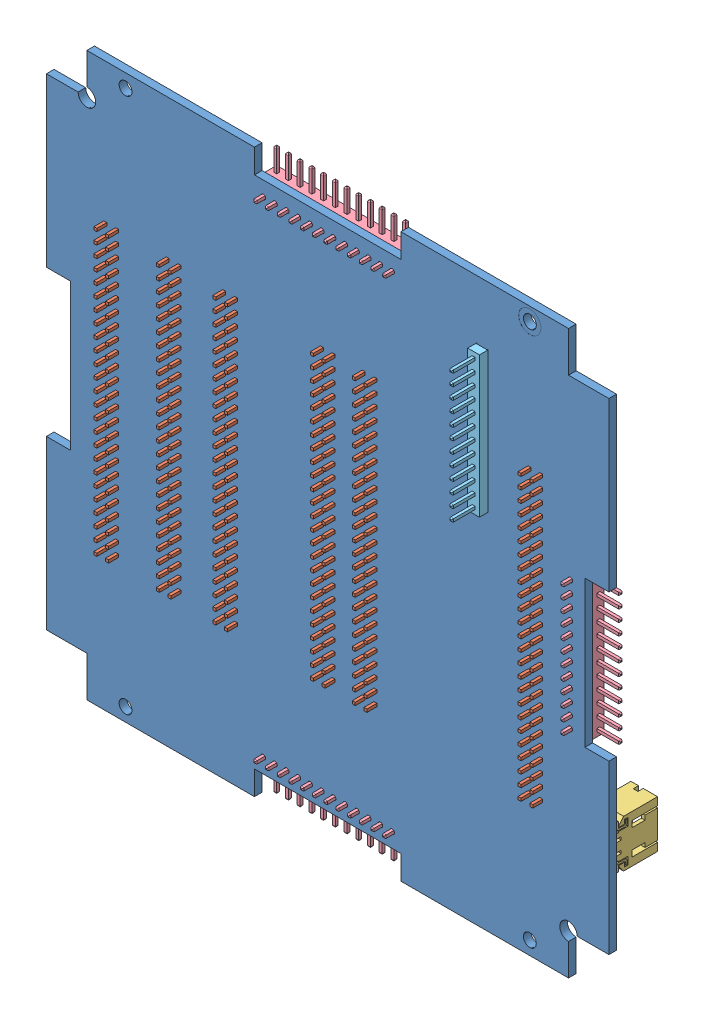
SolidWorks assembly B3_back_board, configuration ﾃﾞﾌｫﾙﾄ. Lengths in mm.
Overall size (96 96 13.7).
13 component instances, 5 part files, 36 mates.
Components (placement in the parent):
- B3_bottom_panel-1: B3_bottom_panel [ﾃﾞﾌｫﾙﾄ] at (2.0992 1.8569 97) size (96 96 1.3)
- B3_50pin-4: B3_50pin [ﾃﾞﾌｫﾙﾄ] at (-24.2008 1.8569 97) x (0 -1 0) z (0 0 -1) size (50 4 7.2)
- B3_50pin-6: B3_50pin [ﾃﾞﾌｫﾙﾄ] at (2.0992 1.8569 97) x (0 -1 0) z (0 0 -1) size (50 4 7.2)
- B3_50pin-8: B3_50pin [ﾃﾞﾌｫﾙﾄ] at (-34.8508 1.8569 97) x (0 -1 0) z (0 0 -1) size (50 4 7.2)
- MOLEX_554600272-1: MOLEX_554600272 [Default] at (-43.6258 27.8069 93.5) x (0 1 0) z (0 0 -1) size (8.1 6.55 7)
- MOLEX_554600272-2: MOLEX_554600272 [Default] at (47.8242 -24.0931 93.5) x (0 -1 0) z (0 0 -1) size (8.1 6.55 7)
- B3_50pin-9: B3_50pin [ﾃﾞﾌｫﾙﾄ] at (37.5492 1.8569 97) x (0 -1 0) z (0 0 -1) size (50 4 7.2)
- B3_50pin-11: B3_50pin [ﾃﾞﾌｫﾙﾄ] at (-14.5508 1.8569 97) x (0 -1 0) z (0 0 -1) size (50 4 7.2)
- Solar_panel_ML-1: Solar_panel_ML [Default] at (-9.9008 45.7569 95) x (0 0 1) z (-1 0 0) size (4.85 6.65 24)
- Solar_panel_ML-2: Solar_panel_ML [Default] at (45.9992 13.8569 95) x (0 0 1) z (0 1 0) size (4.85 6.65 24)
- Solar_panel_ML-3: Solar_panel_ML [Default] at (14.0992 -42.0431 95) x (0 0 1) z (1 0 0) size (4.85 6.65 24)
- Solar panel_M-2: Solar panel_M [Default] at (27.4992 15.8569 99.8) x (1 0 0) z (0 -1 0) size (2 8.15 24)
- B3_50pin-12: B3_50pin [ﾃﾞﾌｫﾙﾄ] at (9.2492 1.8569 97) x (0 1 0) z (0 0 -1) size (50 4 7.2)
Mates (geometry in assembly coordinates):
- Coincident11: coincident anti-aligned: plane of B3_bottom_panel-1 through (2.0992 1.8569 97) normal (0 0 -1); plane of B3_50pin-6 through (2.0992 1.8569 97) normal (0 0 1)
- Coincident14: coincident anti-aligned: plane of B3_bottom_panel-1 through (2.0992 1.8569 97) normal (0 0 -1); plane of B3_50pin-4 through (-24.2008 1.8569 97) normal (0 0 1)
- Coincident35: coincident anti-aligned: plane of B3_bottom_panel-1 through (2.0992 1.8569 97) normal (0 0 -1); plane of B3_50pin-8 through (-34.8508 1.8569 97) normal (0 0 1)
- Coincident36: coincident aligned: plane of B3_50pin-4 through (-26.2008 26.8569 92.8) normal (0 1 0); plane of B3_50pin-8 through (-36.8508 26.8569 92.8) normal (0 1 0)
- Coincident47: coincident aligned: plane of B3_50pin-6 through (0.0992 26.8569 92.8) normal (0 1 0); plane of B3_50pin-8 through (-36.8508 26.8569 92.8) normal (0 1 0)
- Coincident95: coincident anti-aligned: plane of B3_bottom_panel-1 through (2.0992 1.8569 97) normal (0 0 -1); plane of MOLEX_554600272-1 through (-43.6258 27.8069 97) normal (0 0 1)
- Distance46: distance = 11.1 mm aligned: plane of MOLEX_554600272-1 through (-45.9008 31.8569 97) normal (0 1 0); plane of B3_bottom_panel-1 through (-39.0008 42.9569 89.8) normal (0 1 0)
- Coincident101: coincident anti-aligned: plane of B3_bottom_panel-1 through (2.0992 1.8569 97) normal (0 0 -1); plane of MOLEX_554600272-2 through (47.8242 -24.0931 97) normal (0 0 1)
- Distance47: distance = 11.1 mm aligned: plane of MOLEX_554600272-2 through (50.0992 -28.1431 97) normal (0 -1 0); plane of B3_bottom_panel-1 through (50.1992 -39.2431 89.8) normal (0 -1 0)
- Coincident106: coincident anti-aligned: plane of B3_bottom_panel-1 through (2.0992 1.8569 97) normal (0 0 -1); plane of B3_50pin-11 through (-14.5508 1.8569 97) normal (0 0 1)
- Coincident108: coincident anti-aligned: plane of B3_bottom_panel-1 through (2.0992 1.8569 97) normal (0 0 -1); plane of B3_50pin-9 through (37.5492 1.8569 97) normal (0 0 1)
- Coincident109: coincident aligned: plane of B3_50pin-8 through (-36.8508 26.8569 92.8) normal (0 1 0); plane of B3_50pin-11 through (-16.5508 26.8569 92.8) normal (0 1 0)
- Coincident111: coincident aligned: plane of B3_50pin-8 through (-36.8508 26.8569 92.8) normal (0 1 0); plane of B3_50pin-9 through (35.5492 26.8569 92.8) normal (0 1 0)
- Distance49: distance = 4.95 mm aligned: plane of B3_50pin-8 through (-36.8508 26.8569 92.8) normal (-1 0 0); plane of B3_bottom_panel-1 through (-41.8008 14.3569 98.3) normal (-1 0 0)
- Distance50: distance = 15.6 mm aligned: plane of B3_50pin-4 through (-26.2008 26.8569 92.8) normal (-1 0 0); plane of B3_bottom_panel-1 through (-41.8008 14.3569 98.3) normal (-1 0 0)
- Distance51: distance = 25.25 mm aligned: plane of B3_50pin-11 through (-16.5508 26.8569 92.8) normal (-1 0 0); plane of B3_bottom_panel-1 through (-41.8008 14.3569 98.3) normal (-1 0 0)
- Distance53: distance = 41.9 mm aligned: plane of B3_50pin-6 through (0.0992 26.8569 92.8) normal (-1 0 0); plane of B3_bottom_panel-1 through (-41.8008 14.3569 98.3) normal (-1 0 0)
- Distance55: distance = 77.35 mm aligned: plane of B3_50pin-9 through (35.5492 26.8569 92.8) normal (-1 0 0); plane of B3_bottom_panel-1 through (-41.8008 14.3569 98.3) normal (-1 0 0)
- Coincident139: coincident aligned: plane of B3_bottom_panel-1 through (-45.9008 42.9569 98.3) normal (-1 0 0); plane of MOLEX_554600272-1 through (-45.9008 23.7569 97) normal (-1 0 0)
- Coincident140: coincident aligned: plane of B3_bottom_panel-1 through (50.0992 -39.2431 98.3) normal (1 0 0); plane of MOLEX_554600272-2 through (50.0992 -20.0431 97) normal (1 0 0)
- Distance63: distance = 23 mm aligned: plane of B3_50pin-8 through (-36.8508 26.8569 92.8) normal (0 1 0); plane of B3_bottom_panel-1 through (43.1992 49.8569 98.3) normal (0 1 0)
- Coincident142: coincident anti-aligned: plane of B3_bottom_panel-1 through (2.0992 1.8569 97) normal (0 0 -1); plane of Solar_panel_ML-1 through (14.0992 45.7569 97) normal (0 0 1)
- Coincident143: coincident aligned: plane of B3_bottom_panel-1 through (-10.4008 45.7569 98.3) normal (0 1 0); plane of Solar_panel_ML-1 through (14.0992 45.7569 95) normal (0 1 0)
- Distance66: distance = 0.5 mm anti-aligned: plane of Solar_panel_ML-1 through (14.0992 45.7569 95) normal (1 0 0); plane of B3_bottom_panel-1 through (14.5992 45.7569 98.3) normal (-1 0 0)
- Coincident149: coincident anti-aligned: plane of B3_bottom_panel-1 through (2.0992 1.8569 97) normal (0 0 -1); plane of Solar_panel_ML-2 through (45.9992 -10.1431 97) normal (0 0 1)
- Coincident150: coincident aligned: plane of B3_bottom_panel-1 through (45.9992 14.3569 98.3) normal (1 0 0); plane of Solar_panel_ML-2 through (45.9992 -10.1431 95) normal (1 0 0)
- Distance68: distance = 0.5 mm anti-aligned: plane of Solar_panel_ML-2 through (45.9992 -10.1431 95) normal (0 -1 0); plane of B3_bottom_panel-1 through (45.9992 -10.6431 98.3) normal (0 1 0)
- Coincident152: coincident anti-aligned: plane of B3_bottom_panel-1 through (2.0992 1.8569 97) normal (0 0 -1); plane of Solar_panel_ML-3 through (-9.9008 -42.0431 97) normal (0 0 1)
- Coincident153: coincident aligned: plane of B3_bottom_panel-1 through (-10.4008 -42.0431 98.3) normal (0 -1 0); plane of Solar_panel_ML-3 through (-9.9008 -42.0431 95) normal (0 -1 0)
- Distance69: distance = 0.5 mm anti-aligned: plane of Solar_panel_ML-3 through (-9.9008 -42.0431 95) normal (-1 0 0); plane of B3_bottom_panel-1 through (-10.4008 -46.2431 98.3) normal (1 0 0)
- Coincident158: coincident anti-aligned: plane of B3_bottom_panel-1 through (2.0992 1.8569 98.3) normal (0 0 1); plane of Solar panel_M-2 through (29.401 39.8569 98.3) normal (0 0 -1)
- Distance73: distance = 73.4 mm aligned: plane of Solar panel_M-2 through (27.4992 39.8569 99.8) normal (-1 0 0); plane of B3_bottom_panel-1 through (-45.9008 42.9569 98.3) normal (-1 0 0)
- Distance74: distance = 62 mm aligned: plane of Solar panel_M-2 through (27.4992 15.8569 99.8) normal (0 -1 0); plane of B3_bottom_panel-1 through (-39.0008 -46.1431 98.3) normal (0 -1 0)
- 一致1: coincident anti-aligned: plane of B3_bottom_panel-1 through (2.0992 1.8569 97) normal (0 0 -1); plane of B3_50pin-12 through (9.2492 1.8569 97) normal (0 0 1)
- 一致2: coincident aligned: plane of B3_50pin-11 through (-16.5508 -23.1431 92.8) normal (0 -1 0); plane of B3_50pin-12 through (11.2492 -23.1431 92.8) normal (0 -1 0)
- 距離1: distance = 49.05 mm aligned: plane of B3_50pin-12 through (7.2492 -23.1431 92.8) normal (-1 0 0); plane of B3_bottom_panel-1 through (-41.8008 14.3569 98.3) normal (-1 0 0)
